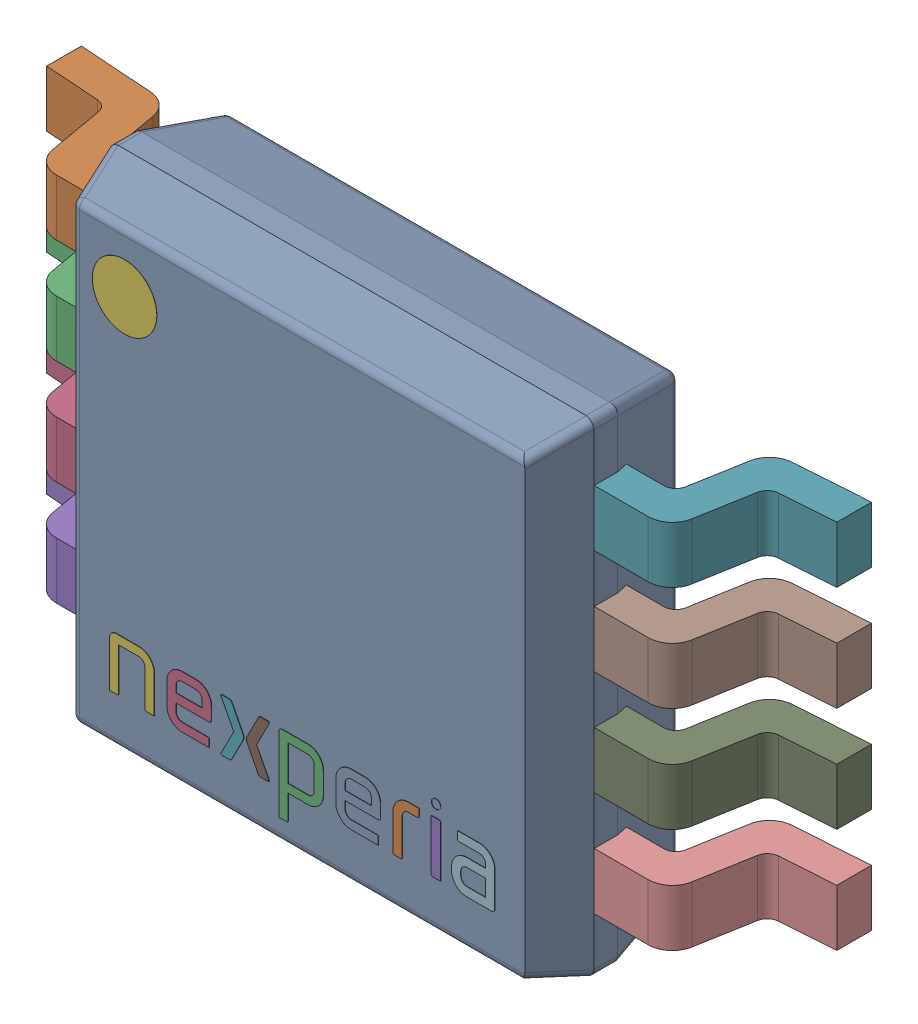
SolidWorks assembly U2, configuration Default. Lengths in mm.
Overall size (4.9 3 1.12).
12 component instances, 5 part files, 0 mates.
Components (placement in the parent):
- IC_NXP_Semiconductors_PCA9517DP_118_eec-1: IC_NXP_Semiconductors_PCA9517DP_118_eec [Default] at (23.106 1.397 0) size (4.9 3 1.12)
  - IC_BODY-1: IC_BODY [Default] at (0 0 0.15) x (0 -1 0) z (0 0 1) size (3 3 0.97)
  - IC_LEG-1: IC_LEG [Default] at (-2.45 1.1495 0) x (1 0 0) z (0 -1 0) size (1.05 0.77 0.35)
  - IC_LEG-2: IC_LEG [Default] at (-2.45 0.4995 0) x (1 0 0) z (0 -1 0) size (1.05 0.77 0.35)
  - IC_LEG-3: IC_LEG [Default] at (-2.45 -0.1505 0) x (1 0 0) z (0 -1 0) size (1.05 0.77 0.35)
  - IC_LEG-4: IC_LEG [Default] at (-2.45 -0.8005 0) x (1 0 0) z (0 -1 0) size (1.05 0.77 0.35)
  - circle-1: circle [Default] at (-1.0817 1.037 1.101) x (1 0 0) z (0 0 -1) size (0.4 0.4 0.01)
  - IC_LEG_MIR5-1: IC_LEG_MIR5 [Default] at (2.45 1.1495 0) x (-1 0 0) z (0 1 0) size (1.05 0.77 0.35)
  - IC_LEG_MIR5-2: IC_LEG_MIR5 [Default] at (2.45 0.4995 0) x (-1 0 0) z (0 1 0) size (1.05 0.77 0.35)
  - IC_LEG_MIR5-3: IC_LEG_MIR5 [Default] at (2.45 -0.1505 0) x (-1 0 0) z (0 1 0) size (1.05 0.77 0.35)
  - IC_LEG_MIR5-4: IC_LEG_MIR5 [Default] at (2.45 -0.8005 0) x (-1 0 0) z (0 1 0) size (1.05 0.77 0.35)
  - Nexperia-1: Nexperia [Default] at (-0.092 -0.9859 1.1) size (2.4 0.59 0.04)
